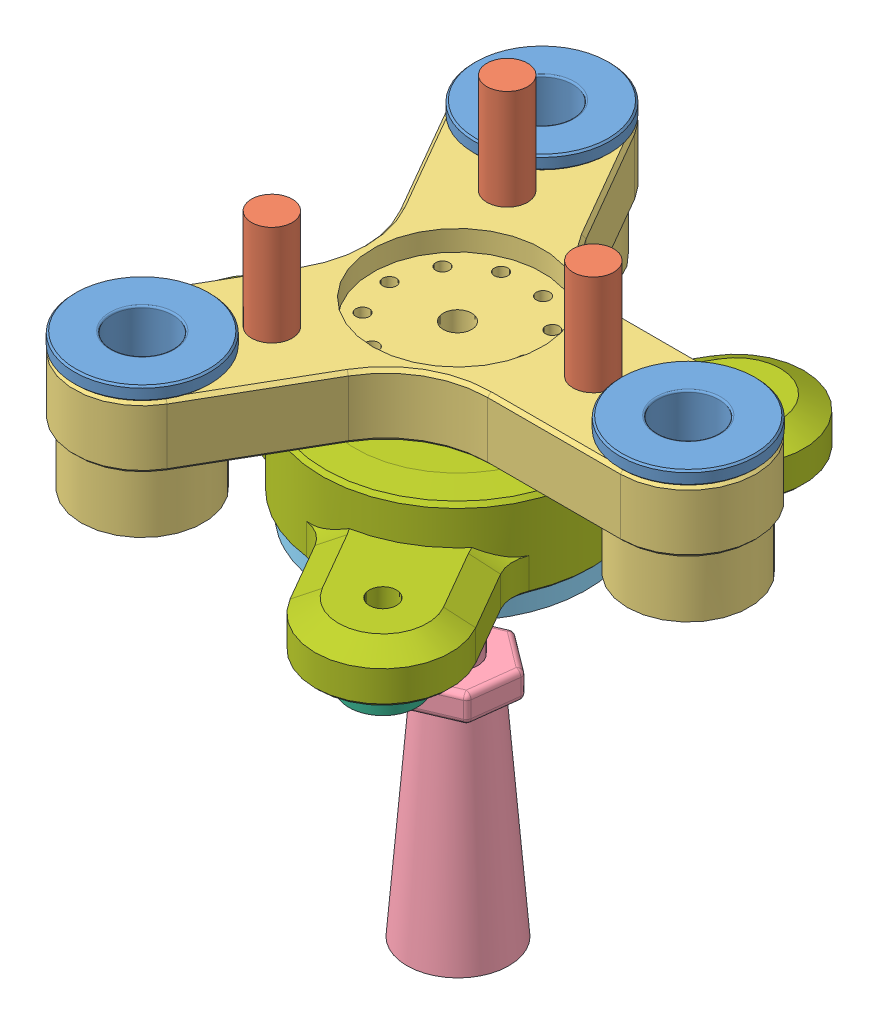
SolidWorks assembly slider, configuration ﾃﾞﾌｫﾙﾄ. Lengths in mm.
Overall size (94.82 96.17 92.27).
15 component instances, 7 part files, 9 mates.
Components (placement in the parent):
- slider_plate_top-1: slider_plate_top [ﾃﾞﾌｫﾙﾄ] at (2.3558 73.6573 50.7874) size (70.95 32.75 78.84)
  - slider_plate_slide-1: slider_plate_slide [ﾃﾞﾌｫﾙﾄ] at (50.5087 -11.925 75.9849) size (20 20 20)
  - slider_plate_slide-2: slider_plate_slide [ﾃﾞﾌｫﾙﾄ] at (-0.4452 -11.925 46.5667) size (20 20 20)
  - slider_plate_slide-3: slider_plate_slide [ﾃﾞﾌｫﾙﾄ] at (-0.4452 -11.925 105.4031) size (20 20 20)
  - slider_plate_stoper-2: slider_plate_stoper [ﾃﾞﾌｫﾙﾄ] at (6.5394 -21.175 58.6644) size (6 27.1 6)
  - slider_plate_stoper-3: slider_plate_stoper [ﾃﾞﾌｫﾙﾄ] at (36.5394 -21.175 75.9849) size (6 27.1 6)
  - slider_plate_stoper-4: slider_plate_stoper [ﾃﾞﾌｫﾙﾄ] at (6.5394 -21.175 93.3054) size (6 27.1 6)
  - slider_plate_top_fixed-1: slider_plate_top_fixed [ﾃﾞﾌｫﾙﾄ] at (16.5394 -21.175 75.9849) size (70.95 18 78.84)
- center_pole-1: center_pole [ﾃﾞﾌｫﾙﾄ] at (18.8953 25.8276 126.7723) size (19 57.52 19)
- slider_plate_bottom-2: slider_plate_bottom [ﾃﾞﾌｫﾙﾄ] at (37.4383 43.7497 70.413) x (0.866025 0 0.5) z (-0.5 0 0.866025) size (71.96 17.5 65)
  - slider_plate_bottom_2-1: slider_plate_bottom_2 [ﾃﾞﾌｫﾙﾄ] at (12.1209 -9.7674 58.0801) size (38 3 38)
  - slider_plate_bottom_pin-2: slider_plate_bottom_pin [ﾃﾞﾌｫﾙﾄ] at (38.1017 -11.2674 73.0801) size (10 4.5 10)
  - slider_plate_bottom_pin-3: slider_plate_bottom_pin [ﾃﾞﾌｫﾙﾄ] at (-13.8599 -11.2674 73.0801) size (10 4.5 10)
  - slider_plate_bottom_pin-4: slider_plate_bottom_pin [ﾃﾞﾌｫﾙﾄ] at (12.1209 -11.2674 28.0801) size (10 4.5 10)
  - slider_plate_bottom_fixed-1: slider_plate_bottom_fixed [ﾃﾞﾌｫﾙﾄ] at (12.1209 -6.7674 58.0801) size (71.96 13 65)
Mates (geometry in assembly coordinates):
- 一致1: coincident anti-aligned: plane of slider_plate_top-1/slider_plate_top_fixed-1 through (18.8953 49.9823 126.7723) normal (0 -1 0); plane of ? through (18.8953 49.9823 126.7723) normal (0 1 0)
- 同心円1: concentric anti-aligned: cylinder of slider_plate_top-1/slider_plate_top_fixed-1 through (18.8953 52.4823 126.7723) axis (0 1 0) radius 2.1; cylinder of ? through (18.8953 49.9833 126.7723) axis (0 -1 0) radius 10
- 平行2: parallel aligned: plane of slider_plate_top-1/slider_plate_top_fixed-1 through (52.8645 61.7323 116.7723) normal (0 0 -1); plane of ? through (18.8953 43.9823 121.7523) normal (0 0 -1)
- 同心円3: concentric: cylinder of ? through (18.8953 33.9813 126.7723) axis (0 1 0) radius 10; cylinder of center_pole-1 through (18.8953 65.3269 126.7723) axis (0 -1 0) radius 8
- 一致4: coincident aligned: plane of ? through (18.8953 33.9823 126.7723) normal (0 -1 0); circle of center_pole-1
- 同心円4: concentric anti-aligned: cylinder of slider_plate_top-1/slider_plate_top_fixed-1 through (18.8953 52.4823 126.7723) axis (0 1 0) radius 2.1; cylinder of slider_plate_bottom-2/slider_plate_bottom_fixed-1 through (18.8953 49.9823 126.7723) axis (0 -1 0) radius 10
- 一致5: coincident anti-aligned: plane of slider_plate_top-1/slider_plate_top_fixed-1 through (18.8953 49.9823 126.7723) normal (0 -1 0); plane of slider_plate_bottom-2/slider_plate_bottom_fixed-1 through (18.8953 49.9823 126.7723) normal (0 1 0)
- 一致6: coincident anti-aligned: circle of center_pole-1; plane of slider_plate_bottom-2/slider_plate_bottom_2-1 through (18.8953 33.9823 126.7723) normal (0 -1 0)
- 一致7: coincident aligned: plane of slider_plate_top-1/slider_plate_top_fixed-1 through (10.5709 61.7323 161.1905) normal (0.866025 0 0.5); plane of slider_plate_bottom-2/slider_plate_bottom_fixed-1 through (27.5555 43.9823 131.7723) normal (0.866025 0 0.5)
